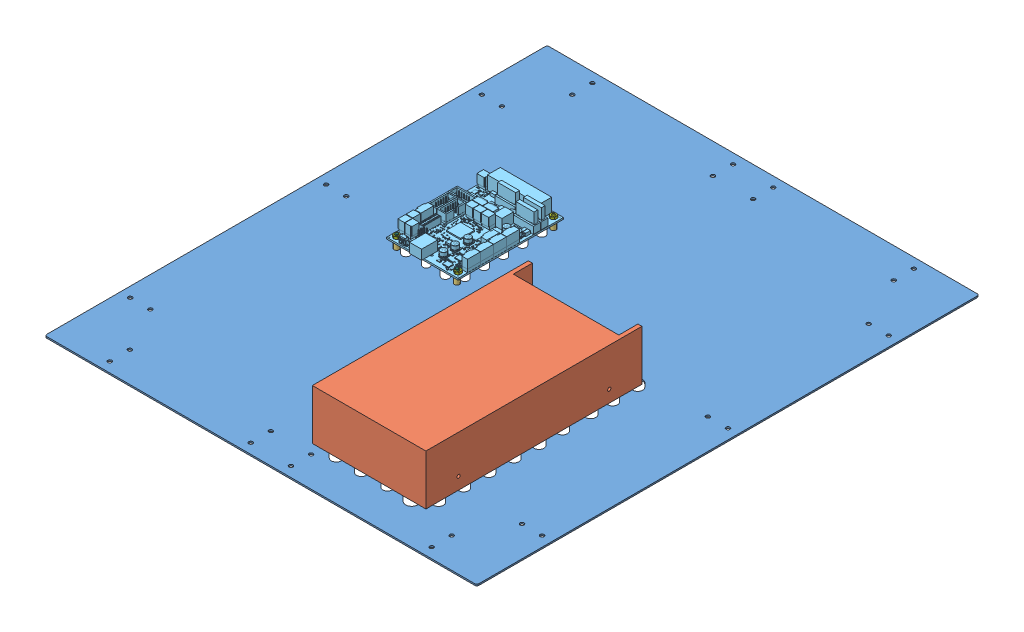
SolidWorks assembly Step12, configuration Default. Lengths in mm.
Overall size (430 61.83 500).
19 component instances, 7 part files, 29 mates.
Components (placement in the parent):
- bottom part-1: bottom part [Default] at (166.7981 148.2872 448.0737) size (430 1.5 500)
- 24V15A power supply-1: 24V15A power supply [Standard] at (234.5908 149.7872 550.5737) x (0 0 -1) z (0 1 0) size (215 113 50)
- 5mm Spacer Electornics-1: 5mm Spacer Electornics [Default] at (47.7255 149.7872 438.7378) x (-0.243762 0 -0.969835) z (0.969835 0 -0.243762) size (5 8 5)
- 5mm Spacer Electornics-2: 5mm Spacer Electornics [Default] at (57.4651 149.7872 344.6069) x (0.698624 0 -0.715489) z (0.715489 0 0.698624) size (5 8 5)
- 5mm Spacer Electornics-3: 5mm Spacer Electornics [Default] at (110.6804 149.7872 437.9284) x (0.060757 0 -0.998153) z (0.998153 0 0.060757) size (5 8 5)
- 5mm Spacer Electornics-4: 5mm Spacer Electornics [Default] at (120.3443 149.7872 359.4927) x (0.625212 0 0.780455) z (-0.780455 0 0.625212) size (5 8 5)
- M4 Screw-1: M4 Screw [По умолчанию] at (259.0908 141.9574 626.0737) x (0.93383 0 -0.357716) z (-0.357716 0 -0.93383) size (7 22 7)
- M4 Screw-2: M4 Screw [По умолчанию] at (209.0908 142.9731 626.0737) x (0.931481 0 -0.36379) z (-0.36379 0 -0.931481) size (7 22 7)
- M4 Screw-3: M4 Screw [По умолчанию] at (259.0908 143.9377 476.0737) x (0.856133 0 -0.516756) z (-0.516756 0 -0.856133) size (7 22 7)
- M4 Screw-4: M4 Screw [По умолчанию] at (209.0908 144.393 476.0737) x (0.81179 0 -0.583949) z (-0.583949 0 -0.81179) size (7 22 7)
- Einsy_Rambo-3: Einsy_Rambo [Default] at (60.7189 159.3819 430.4023) x (0 0 -1) z (0 1 0) size (108.28 71 21.5)
- M3 Screw-1: M3 Screw [92095A177] at (111.8181 142.9011 352.8813) x (0.989153 0 -0.146886) z (0 -1 0) size (5.7 5.7 6.94)
- M3 Screw-2: M3 Screw [92095A177] at (51.8181 156.0898 447.8813) x (0.973328 0 -0.229419) z (0 -1 0) size (5.7 5.7 6.94)
- M3 Screw-3: M3 Screw [92095A177] at (51.8181 155.9823 352.8813) x (0.43295 0 -0.901418) z (0 -1 0) size (5.7 5.7 6.94)
- M3 Screw-4: M3 Screw [92095A177] at (111.8181 156.0907 447.8813) x (0.986847 0 0.161657) z (0 -1 0) size (5.7 5.7 6.94)
- M3 Nut-1: M3 Nut [90591A250] at (112.8181 160.5819 352.8813) x (1 0 0) z (0 -1 0) size (5.5 6.35 2.78)
- M3 Nut-2: M3 Nut [90591A250] at (112.8181 160.5819 447.8813) x (1 0 0) z (0 -1 0) size (5.5 6.35 2.78)
- M3 Nut-3: M3 Nut [90591A250] at (51.8181 160.5819 352.8813) x (1 0 0) z (0 -1 0) size (5.5 6.35 2.78)
- M3 Nut-4: M3 Nut [90591A250] at (51.8181 160.5819 447.8813) x (1 0 0) z (0 -1 0) size (5.5 6.35 2.78)
Mates (geometry in assembly coordinates):
- Concentric2: concentric aligned: circle of bottom part-1; circle of 5mm Spacer Electornics-1
- Concentric3: concentric aligned: circle of bottom part-1; circle of 5mm Spacer Electornics-2
- Concentric5: concentric aligned: circle of bottom part-1; circle of 5mm Spacer Electornics-3
- Coincident1: coincident anti-aligned: plane of bottom part-1 through (166.7981 149.7872 448.0737) normal (0 1 0); plane of 5mm Spacer Electornics-2 through (51.8181 149.7872 352.8813) normal (0 -1 0)
- Coincident3: coincident anti-aligned: plane of bottom part-1 through (166.7981 149.7872 448.0737) normal (0 1 0); plane of 5mm Spacer Electornics-3 through (111.8181 149.7872 447.8813) normal (0 -1 0)
- Coincident4: coincident anti-aligned: plane of bottom part-1 through (166.7981 149.7872 448.0737) normal (0 1 0); plane of 5mm Spacer Electornics-4 through (112.8181 149.7872 352.8813) normal (0 -1 0)
- Coincident5: coincident anti-aligned: plane of bottom part-1 through (166.7981 149.7872 448.0737) normal (0 1 0); plane of 5mm Spacer Electornics-1 through (51.8181 149.7872 447.8813) normal (0 -1 0)
- Concentric13: concentric anti-aligned: circle of bottom part-1; circle of 24V15A power supply-1
- Concentric14: concentric anti-aligned: circle of bottom part-1; circle of 24V15A power supply-1
- Concentric15: concentric anti-aligned: circle of bottom part-1; circle of M4 Screw-1
- Concentric16: concentric anti-aligned: circle of bottom part-1; circle of M4 Screw-2
- Concentric17: concentric anti-aligned: circle of bottom part-1; circle of M4 Screw-4
- Concentric20: concentric anti-aligned: circle of bottom part-1; circle of M4 Screw-3
- Coincident6: coincident anti-aligned: plane of 5mm Spacer Electornics-1 through (51.8181 157.7872 447.8813) normal (0 1 0); plane of Einsy_Rambo-3 through (117.8179 157.7872 452.8813) normal (0 -1 0)
- Concentric21: concentric anti-aligned: circle of 5mm Spacer Electornics-1; circle of Einsy_Rambo-3
- Concentric23: concentric aligned: cylinder of 5mm Spacer Electornics-4 through (112.8181 157.7872 352.8813) axis (0 -1 0) radius 1.8; circle of Einsy_Rambo-3
- Concentric24: concentric anti-aligned: circle of 5mm Spacer Electornics-1; circle of Einsy_Rambo-3
- Concentric25: concentric aligned: circle of bottom part-1; circle of M3 Screw-3
- Concentric26: concentric aligned: circle of bottom part-1; circle of M3 Screw-2
- Concentric27: concentric aligned: circle of bottom part-1; circle of M3 Screw-1
- Concentric28: concentric aligned: circle of bottom part-1; circle of M3 Screw-4
- Coincident7: coincident anti-aligned: plane of Einsy_Rambo-3 through (117.8179 159.3819 452.8813) normal (0 1 0); plane of M3 Nut-4 through (49.0681 159.3819 449.469) normal (0 -1 0)
- Coincident8: coincident anti-aligned: plane of Einsy_Rambo-3 through (117.8179 159.3819 452.8813) normal (0 1 0); plane of M3 Nut-2 through (110.0681 159.3819 449.469) normal (0 -1 0)
- Coincident9: coincident anti-aligned: plane of Einsy_Rambo-3 through (117.8179 159.3819 452.8813) normal (0 1 0); plane of M3 Nut-3 through (49.0681 159.3819 354.469) normal (0 -1 0)
- Coincident10: coincident anti-aligned: plane of Einsy_Rambo-3 through (117.8179 159.3819 452.8813) normal (0 1 0); plane of M3 Nut-1 through (110.0681 159.3819 354.469) normal (0 -1 0)
- Concentric29: concentric anti-aligned: circle of Einsy_Rambo-3; circle of M3 Nut-1
- Concentric30: concentric anti-aligned: circle of Einsy_Rambo-3; circle of M3 Nut-2
- Concentric31: concentric anti-aligned: circle of Einsy_Rambo-3; circle of M3 Nut-4
- Concentric32: concentric anti-aligned: circle of Einsy_Rambo-3; circle of M3 Nut-3
